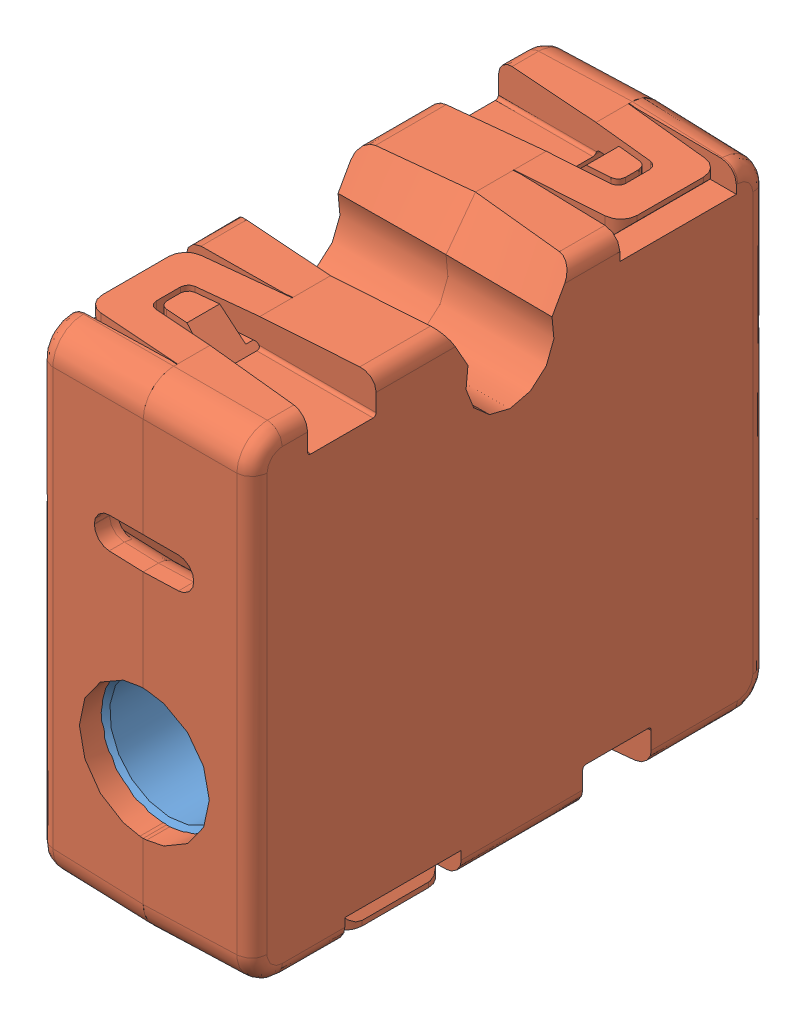
SolidWorks assembly Каретка, configuration По умолчанию. Lengths in mm.
Overall size (14.01 31.51 34.01).
3 component instances, 2 part files, 4 mates.
Components (placement in the parent):
- 1056-A2P-A-1: 1056-A2P-A [По умолчанию] at (15.302 21.8469 -0.0507) x (0.998563 0.053596 0) z (0 0 1) size (11 11 30)
- 1255-B2P-A-1: 1255-B2P-A [По умолчанию] at (15.302 21.8469 -0.6456) size (13.51 31.51 34.01)
- 1255-B2P-A-2: 1255-B2P-A [По умолчанию] at (15.302 21.8469 -0.6456) x (-1 0 0) z (0 0 -1) size (13.51 31.51 34.01)
Mates (geometry in assembly coordinates):
- Концентричный1: concentric aligned: cylinder of 1056-A2P-A-1 through (15.302 21.8469 14.9493) axis (0 0 -1) radius 5.5; cylinder of 1255-B2P-A-1 through (15.302 21.8469 -17.6456) axis (0 0 -1) radius 4.25
- Концентричный3: concentric aligned: cone of 1255-B2P-A-1 through (10.2976 36.8469 -10.6456) axis (1 0 0); circle of 1255-B2P-A-2
- Концентричный4: concentric aligned: cone of 1255-B2P-A-1 through (19.8063 36.8469 9.3544) axis (-1 0 0); cone of 1255-B2P-A-2 through (20.3063 36.8469 9.3544) axis (-1 0 0)
- Совпадение18: coincident anti-aligned: plane of 1255-B2P-A-1 through (15.302 39.8469 -0.6456) normal (1 0 0); plane of 1255-B2P-A-2 through (15.302 39.8469 -0.6456) normal (-1 0 0)
